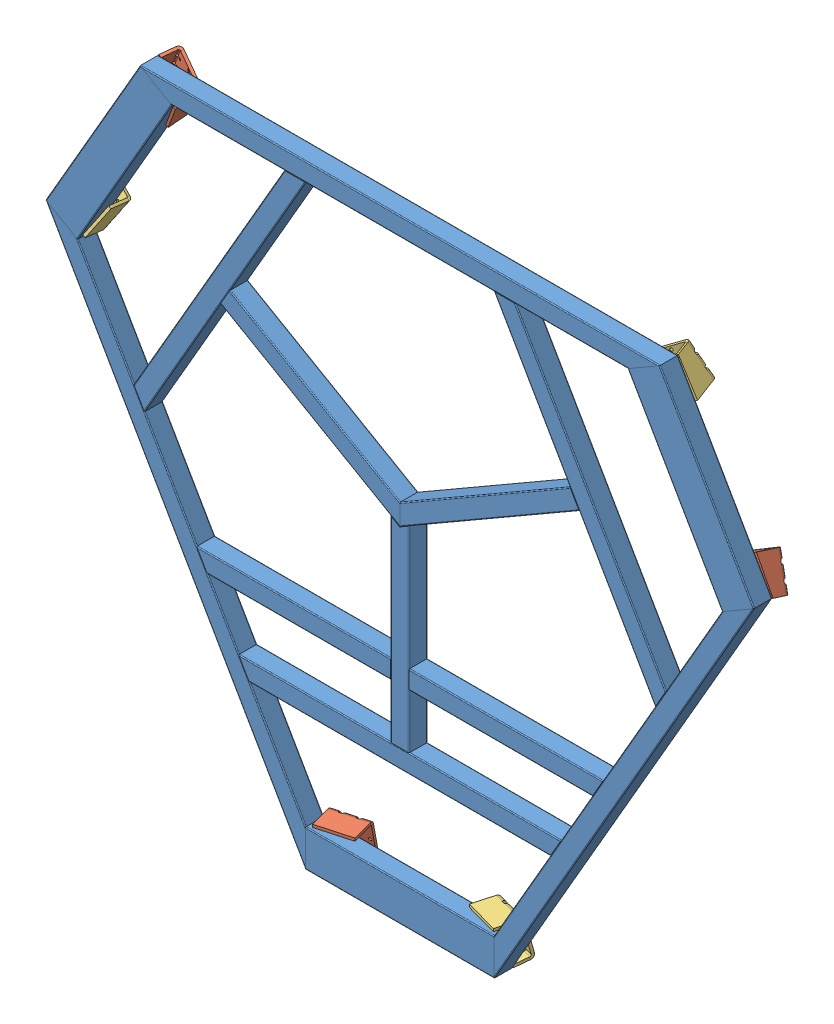
SolidWorks assembly Frame Boven Assembly, configuration Default. Lengths in mm.
Overall size (1549.3 1348.03 99.27).
7 component instances, 3 part files, 18 mates.
Components (placement in the parent):
- Frame boven-1: Frame boven [Default<As Machined>] at (1748.9688 -405.8724 494.777) x (1 0 0) z (0 -1 0) size (1540 40 1333.68)
- Base left-12: Base left [Default] at (1401.8582 -394.1367 442.8059) x (0.963822 0 -0.266548) z (-0.064484 -0.970296 -0.23317) size (75 61.12 94.89)
- Base left-13: Base left [Default] at (2272.3608 621.3323 442.8059) x (-0.481911 0.834694 -0.266548) z (0.872543 0.429303 -0.23317) size (75 61.12 94.89)
- Base left-14: Base left [Default] at (957.6875 867.4752 442.8059) x (-0.481911 -0.834694 -0.266548) z (-0.808059 0.540992 -0.23317) size (75 61.12 94.89)
- Base right-7: Base right [Default] at (1681.5656 -326.216 459.1277) x (-0.963822 0 -0.266548) z (-0.064484 0.970296 0.23317) size (75 61.12 94.89)
- Base right-8: Base right [Default] at (2073.686 829.6057 459.1277) x (0.481911 -0.834694 -0.266548) z (-0.808059 -0.540992 0.23317) size (75 61.12 94.89)
- Base right-9: Base right [Default] at (876.6548 591.2811 459.1277) x (0.481911 0.834694 -0.266548) z (0.872543 -0.429303 0.23317) size (75 61.12 94.89)
Mates (geometry in assembly coordinates):
- Coincident67: coincident: plane of Frame boven-1 through (2312.2368 571.7363 494.777) normal (0 0 -1); line of Base right-8 through (2145.52 859.695 494.777) axis (-0.536083 0.844165 0)
- Coincident68: coincident: plane of Frame boven-1 through (2312.2368 571.7363 494.777) normal (0 0 -1); line of Base left-13 through (2309.3205 569.414 494.777) axis (-0.463027 0.886344 0)
- Coincident69: coincident: plane of Frame boven-1 through (1338.9688 -403.8724 494.777) normal (0 0 -1); line of Base right-7 through (1671.7067 -403.4707 494.777) axis (0.99911 0.042179 0)
- Coincident70: coincident: plane of Frame boven-1 through (1338.9688 -403.8724 494.777) normal (0 0 -1); line of Base left-12 through (1338.4157 -400.1856 494.777) axis (0.99911 -0.042179 0)
- Coincident71: coincident: plane of Frame boven-1 through (980.7009 926.8068 494.777) normal (0 0 -1); line of Base right-9 through (814.6797 638.4465 494.777) axis (-0.463027 -0.886344 0)
- Coincident72: coincident: plane of Frame boven-1 through (980.7009 926.8068 494.777) normal (0 0 -1); line of Base left-14 through (984.1702 925.4424 494.777) axis (-0.536083 -0.844165 0)
- Coincident73: coincident anti-aligned: plane of Frame boven-1 through (2244.6868 532.7363 496.777) normal (-0.866025 -0.5 0); plane of Base right-8 through (2073.447 829.3323 459.5517) normal (0.866025 0.5 0)
- Coincident74: coincident: point of Frame boven-1; line of Base right-8 through (2037.5689 891.4751 481.4605) axis (0.133274 -0.230837 0.963822)
- Coincident75: coincident anti-aligned: plane of Frame boven-1 through (2244.6868 532.7363 496.777) normal (-0.866025 -0.5 0); plane of Base left-13 through (2220.2557 575.0522 392.0842) normal (0.866025 0.5 0)
- Coincident76: coincident: point of Frame boven-1; line of Base left-13 through (2240.4062 540.1506 527.7339) axis (0.133274 -0.230837 -0.963822)
- Coincident78: coincident anti-aligned: plane of Frame boven-1 through (1338.9688 -325.8724 496.777) normal (0 1 0); plane of Base right-7 through (1681.4484 -325.8724 459.5517) normal (0 -1 0)
- Coincident79: coincident: point of Frame boven-1; line of Base right-7 through (1753.2046 -325.8724 481.4605) axis (-0.266548 0 0.963822)
- Coincident80: coincident anti-aligned: plane of Frame boven-1 through (1338.9688 -325.8724 496.777) normal (0 1 0); plane of Base left-12 through (1387.8309 -325.8724 392.0842) normal (0 -1 0)
- Coincident81: coincident: point of Frame boven-1; line of Base left-12 through (1347.53 -325.8724 527.7339) axis (-0.266548 0 -0.963822)
- Coincident82: coincident anti-aligned: plane of Frame boven-1 through (1048.2508 887.8068 496.777) normal (0.866025 -0.5 0); plane of Base right-9 through (877.0111 591.2108 459.5517) normal (-0.866025 0.5 0)
- Coincident83: coincident: point of Frame boven-1; line of Base right-9 through (841.1329 529.068 481.4605) axis (0.133274 0.230837 0.963822)
- Coincident84: coincident anti-aligned: plane of Frame boven-1 through (1048.2508 887.8068 496.777) normal (0.866025 -0.5 0); plane of Base left-14 through (1023.8198 845.4909 392.0842) normal (-0.866025 0.5 0)
- Coincident85: coincident: point of Frame boven-1; line of Base left-14 through (1043.9702 880.3926 527.7339) axis (0.133274 0.230837 -0.963822)
